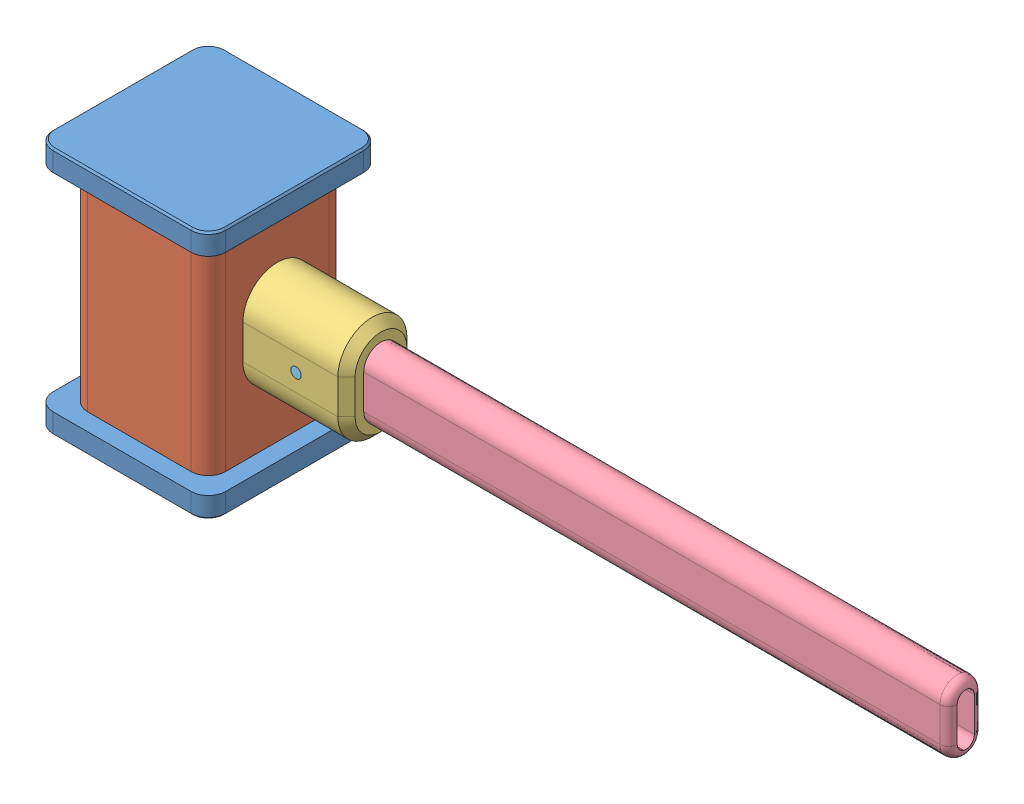
SolidWorks assembly Assem12, configuration Default. Lengths in mm.
Overall size (488.75 144 100).
6 component instances, 5 part files, 10 mates.
Components (placement in the parent):
- Part1-6: Part1 [Default] at (45.0325 20.0768 87.9863) x (-1 0 0) z (0 0 1) size (100 12 100)
- Part2-2: Part2 [Default] at (45.0325 86.0768 87.9863) size (80 120 80)
- Part1-7: Part1 [Default] at (45.0325 152.0768 87.9863) x (-1 0 0) z (0 0 -1) size (100 12 100)
- Part3-1: Part3 [Default] at (115.0325 136.0768 87.9863) x (0 1 0) z (0 0 -1) size (60 60 40)
- Part4-1: Part4 [Default] at (283.7825 81.0768 87.9863) x (0 -1 0) z (0 0 1) size (40 400 20)
- Part5-1: Part5 [Default] at (115.7825 86.0768 87.9863) x (0.152951 -0.988234 0) z (0.988234 0.152951 0) size (6 40 6)
Mates (geometry in assembly coordinates):
- Coincident5: coincident aligned: plane of Part1-6 through (45.0325 20.0768 87.9863) normal (0 0 1); plane of Part2-2 through (45.0325 86.0768 87.9863) normal (0 0 1)
- Coincident6: coincident anti-aligned: plane of Part1-6; plane of Part2-2 through (45.0325 86.0768 87.9863) normal (1 0 0)
- Coincident7: coincident anti-aligned: plane of Part1-6 through (85.0325 26.0768 127.9863) normal (0 1 0); plane of Part2-2 through (75.0325 26.0768 117.9863) normal (0 -1 0)
- Distance1: distance = 20 mm aligned: plane of Part2-2 through (15.0325 146.0768 127.9863) normal (0 0 1); plane of Part3-1 through (145.0325 76.0768 107.9863) normal (0 0 1)
- Distance2: distance = 72 mm: plane of Part1-7 through (85.0325 158.0768 47.9863) normal (0 1 0); axis of Part3-1 through (115.7825 86.0768 77.9863) axis (0 0 -1)
- Coincident10: coincident anti-aligned: plane of Part2-2 through (85.0325 146.0768 117.9863) normal (1 0 0); plane of Part3-1 through (85.0325 76.0768 87.9863) normal (-1 0 0)
- Concentric1: concentric anti-aligned: cylinder of Part3-1 through (115.7825 86.0768 107.9863) axis (0 0 -1) radius 3; cylinder of Part4-1 through (115.7825 86.0768 77.9863) axis (0 0 1) radius 3
- Concentric2: concentric aligned: cylinder of Part3-1 through (145.0325 96.0768 87.9863) axis (-1 0 0) radius 10; cylinder of Part4-1 through (483.7825 96.0768 87.9863) axis (-1 0 0) radius 10
- Concentric4: concentric anti-aligned: cylinder of Part3-1 through (115.7825 86.0768 107.9863) axis (0 0 -1) radius 3; cylinder of Part5-1 through (115.7825 86.0768 67.9863) axis (0 0 1) radius 3
- Coincident13: coincident aligned: plane of Part3-1 through (145.0325 76.0768 107.9863) normal (0 0 1); plane of Part5-1 through (115.7825 86.0768 107.9863) normal (0 0 1)
